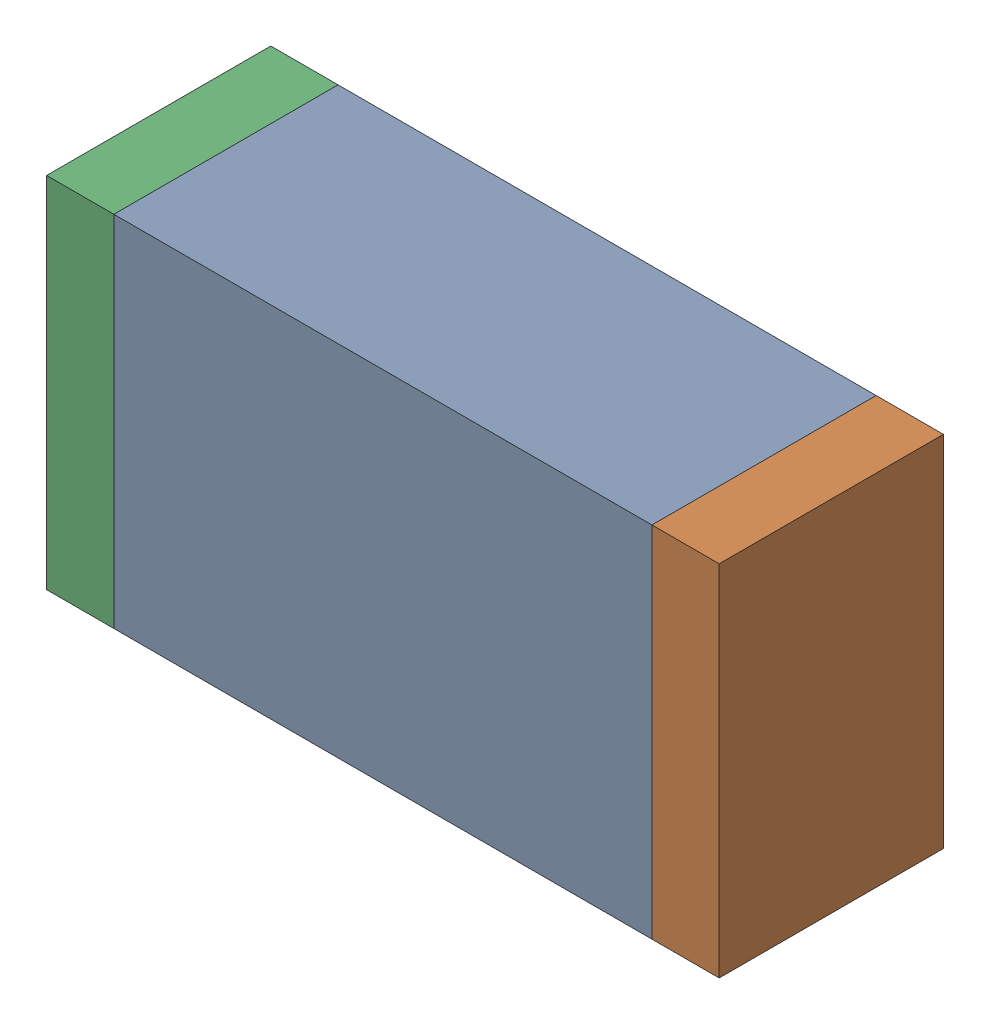
SolidWorks assembly R18, configuration Default. Lengths in mm.
Overall size (1.5 0.8 0.5).
6 component instances, 2 part files, 0 mates.
Components (placement in the parent):
- 836752368-1: 836752368 [Default] at (115.9 40.75 0) size (1.2 0.8 0.5)
  - Extruded-1: Extruded [Default] at origin size (1.2 0.8 0.5)
- 836752496-1: 836752496 [Default] at (116.575 40.75 0) size (0.15 0.8 0.5)
  - Extruded_2-1: Extruded_2 [Default] at origin size (0.15 0.8 0.5)
- 836752496-2: 836752496 [Default] at (115.225 40.75 0) size (0.15 0.8 0.5)
  - Extruded_2-1: Extruded_2 [Default] at origin size (0.15 0.8 0.5)
